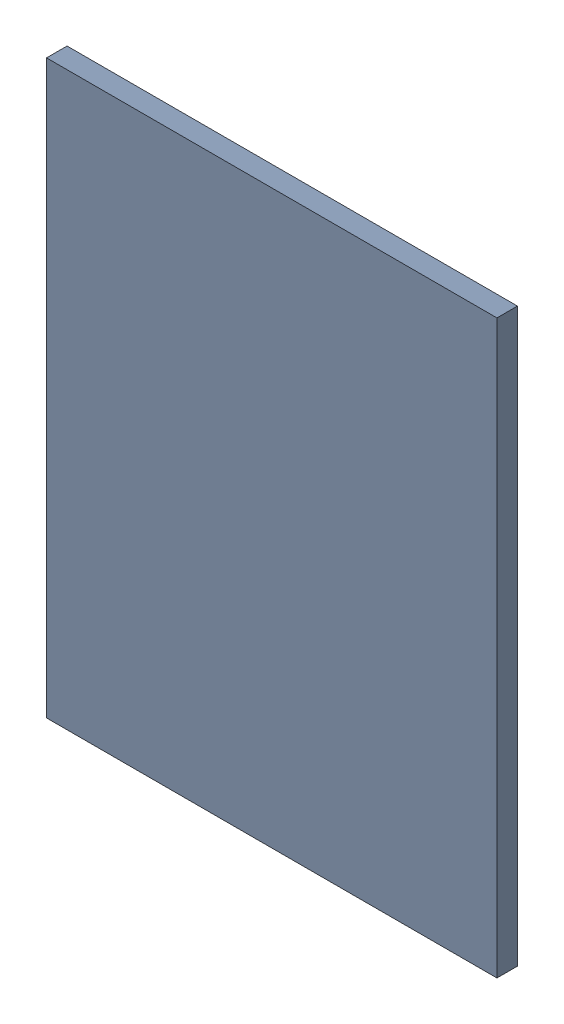
SolidWorks assembly Pad C2-2(27.8mm,43.5mm) on Top Layer, configuration Predeterminado. Lengths in mm.
Overall size (0.78 0.99 0.04).
2 component instances, 1 part files, 0 mates.
Components (placement in the parent):
- Pad C2-2(27.8mm,43.5mm) on Top Layer-1-1: Pad C2-2(27.8mm,43.5mm) on Top Layer-1 [Predeterminado] at (-68.317 -44.187 -0.0457) size (0.78 0.99 0.04)
  - Pad C2-2(27.8mm,43.5mm) on Top Layer-Part-1-1: Pad C2-2(27.8mm,43.5mm) on Top Layer-Part-1 [Predeterminado] at origin size (0.78 0.99 0.04)
